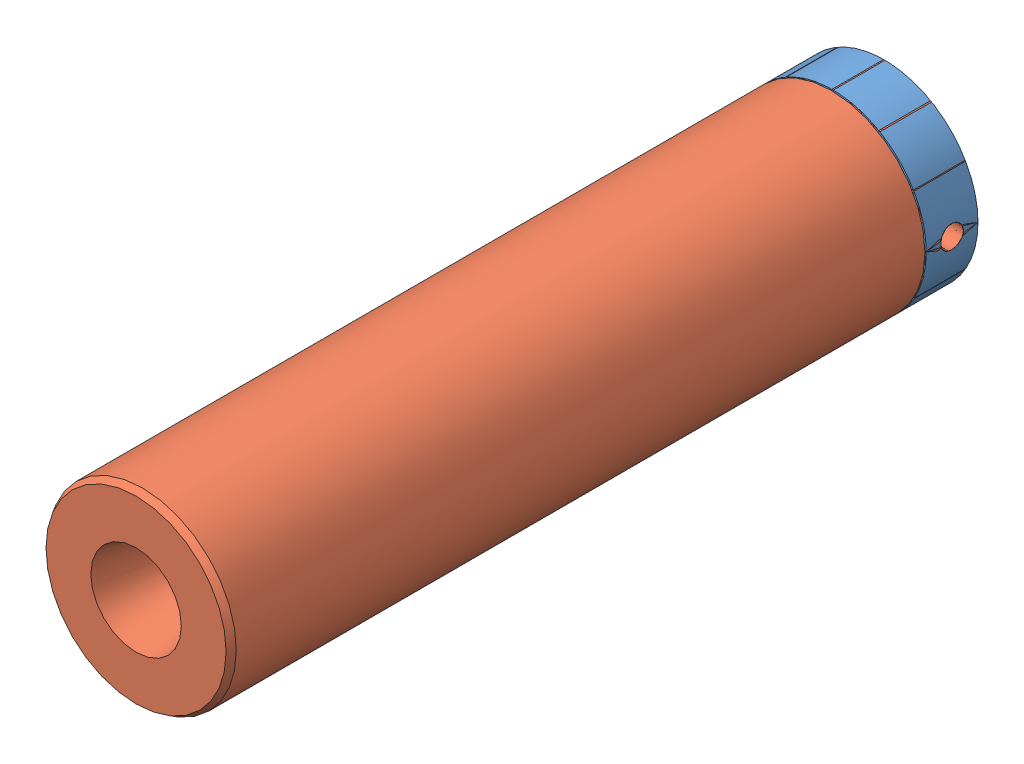
SolidWorks assembly Moteur, configuration Défaut. Lengths in mm.
Overall size (29 29 115.67).
2 component instances, 2 part files, 6 mates.
Components (placement in the parent):
- Bouchon-1: Bouchon [Défaut] at (0 0 -50.3375) x (1 0 0) z (0 0 -1) size (29 29 23.58)
- Chambre combustion-1: Chambre combustion [Défaut] at origin size (29 29 115.67)
Mates (geometry in assembly coordinates):
- Coïncidente1: coincident aligned: plane of Chambre combustion-1 through (0 0 0) normal (0 0 1)
- Coïncidente2: coincident aligned: plane of Chambre combustion-1 through (0 0 0) normal (0 1 0)
- Coïncidente3: coincident aligned: plane of Chambre combustion-1 through (0 0 0) normal (1 0 0)
- Coaxiale1: concentric anti-aligned: cylinder of Bouchon-1 through (0 0 -61.8375) axis (0 0 -1) radius 14.5; cylinder of Chambre combustion-1 through (0 0 53.8375) axis (0 0 1) radius 14.5
- Distance1: distance = 0.2 mm anti-aligned: plane of Bouchon-1 through (0 -14.5 -53.8375) normal (0 0 1); plane of Chambre combustion-1 through (0 -14.5 -53.6375) normal (0 0 -1)
- Coïncidente5: coincident aligned: plane of Bouchon-1 through (0 0 -50.3375) normal (1 0 0)
